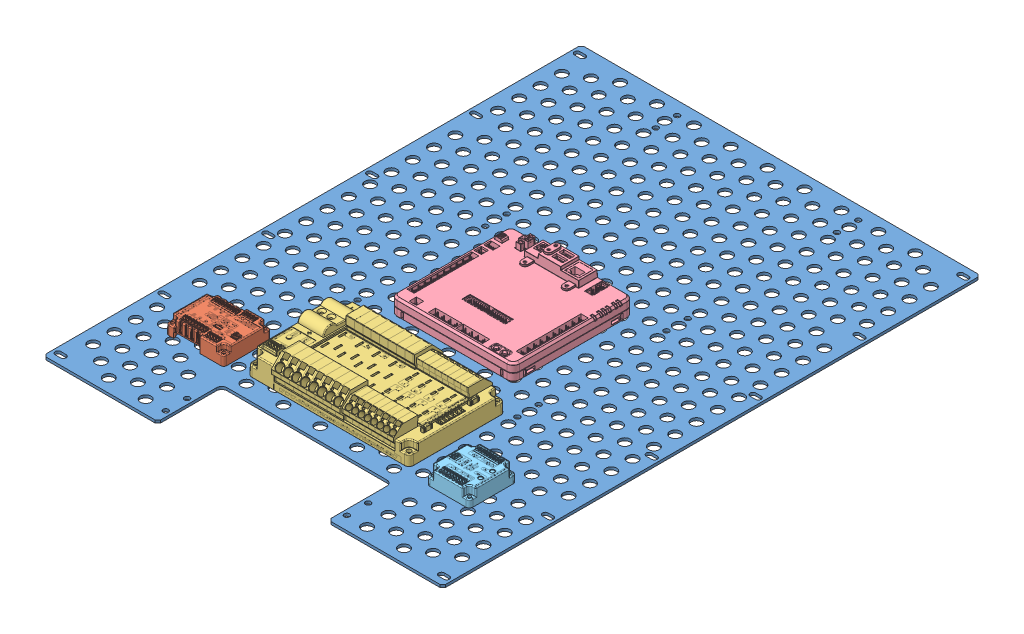
SolidWorks assembly Electronics, configuration Default. Lengths in mm.
Overall size (476.25 42.42 641.35).
5 component instances, 5 part files, 16 mates.
Components (placement in the parent):
- Electronins Board-1: Electronins Board [Default] at origin size (476.25 3.17 641.35)
- Pneumatic Control Module-1: Pneumatic Control Module [Default] at (-152.781 4.4704 196.977) x (-1 0 0) z (0 0 -1) size (69.09 19.67 56.9)
- PowerDistributionPanel-1: PowerDistributionPanel [Default] at (4.318 6.6802 161.6755) size (192.68 39.24 124.89)
- roboRIO-1: roboRIO [Default] at (0 9.652 0) x (1 0 0) z (0 1 0) size (146.27 143.19 36.83)
- VoltageRegulatorModule-1: VoltageRegulatorModule [Default] at (150.7598 7.1314 197.7626) x (0 0 1) z (-1 0 0) size (56.39 27.88 51.56)
Mates (geometry in assembly coordinates):
- Coincident1: coincident aligned: plane of Electronins Board-1 through (0 0 0) normal (1 0 0)
- Coincident2: coincident aligned: plane of Electronins Board-1 through (0 0 0) normal (0 1 0)
- Coincident3: coincident aligned: plane of Electronins Board-1 through (0 0 0) normal (0 0 1)
- Coincident4: coincident anti-aligned: plane of Electronins Board-1 through (0 0 0) normal (0 1 0); plane of PowerDistributionPanel-1 through (91.1352 0 109.4785) normal (0 -1 0)
- Coincident5: coincident aligned: plane of Electronins Board-1 through (0 0 0) normal (0 1 0); plane of roboRIO-1 through (-73.512 0 71.9666) normal (0 1 0)
- Coincident6: coincident anti-aligned: plane of Electronins Board-1 through (0 0 0) normal (0 1 0); plane of Pneumatic Control Module-1 through (-121.793 0 221.869) normal (0 -1 0)
- Coincident7: coincident anti-aligned: plane of Electronins Board-1 through (0 0 0) normal (0 1 0); plane of VoltageRegulatorModule-1 through (170.307 0 221.107) normal (0 -1 0)
- Width1: width aligned: plane of roboRIO-1 through (-73.0758 2.2322 -66.5287) normal (1 0 0); plane of roboRIO-1 through (73.0758 2.2322 66.5287) normal (-1 0 0); plane of Electronins Board-1 through (238.125 -3.175 320.675) normal (1 0 0); plane of Electronins Board-1 through (-238.125 -3.175 320.675) normal (-1 0 0)
- Distance1: distance = 101.6 mm anti-aligned: plane of roboRIO-1 through (-68.074 2.2322 71.5899) normal (0 0 -1); plane of Electronins Board-1 through (231.775 -3.175 320.675) normal (0 0 1)
- Width3: width anti-aligned: plane of PowerDistributionPanel-1 through (-96.3422 0 219.0795) normal (-0.999848 0.017452 0); plane of Electronins Board-1 through (96.3422 0 104.2715) normal (0.999848 0.017452 0); plane of PowerDistributionPanel-1 through (-238.125 -3.175 320.675) normal (-1 0 0); plane of Electronins Board-1 through (238.125 -3.175 320.675) normal (1 0 0)
- Distance3: distance = 101.6 mm: line of PowerDistributionPanel-1 through (86.5587 0.2584 219.075) axis (-1 0 0); plane of Electronins Board-1 through (238.125 -3.175 320.675) normal (0 0 1)
- Distance4: distance = 95.25 mm: line of Pneumatic Control Module-1 through (-146.558 0 225.425) axis (1 0 0); plane of Electronins Board-1 through (238.125 -3.175 320.675) normal (0 0 1)
- Distance5: distance = 50.8 mm: line of Pneumatic Control Module-1 through (-187.325 0 172.085) axis (0 0 1); plane of Electronins Board-1 through (-238.125 -3.175 320.675) normal (-1 0 0)
- Distance6: distance = 95.25 mm: line of VoltageRegulatorModule-1 through (127.381 0 225.425) axis (1 0 0); plane of Electronins Board-1 through (238.125 -3.175 320.675) normal (0 0 1)
- Distance7: distance = 63.5 mm: line of VoltageRegulatorModule-1 through (174.625 0 221.107) axis (0 0 -1); plane of Electronins Board-1 through (238.125 -3.175 320.675) normal (1 0 0)
- Width4: width aligned: plane of Electronins Board-1 through (238.125 -3.175 320.675) normal (0 0 1); plane of Electronins Board-1 through (238.125 -3.175 -320.675) normal (0 0 -1); plane of roboRIO-1 through (68.074 2.2322 -71.5899) normal (0 0 1); plane of roboRIO-1 through (-68.074 2.2322 71.5899) normal (0 0 -1)
